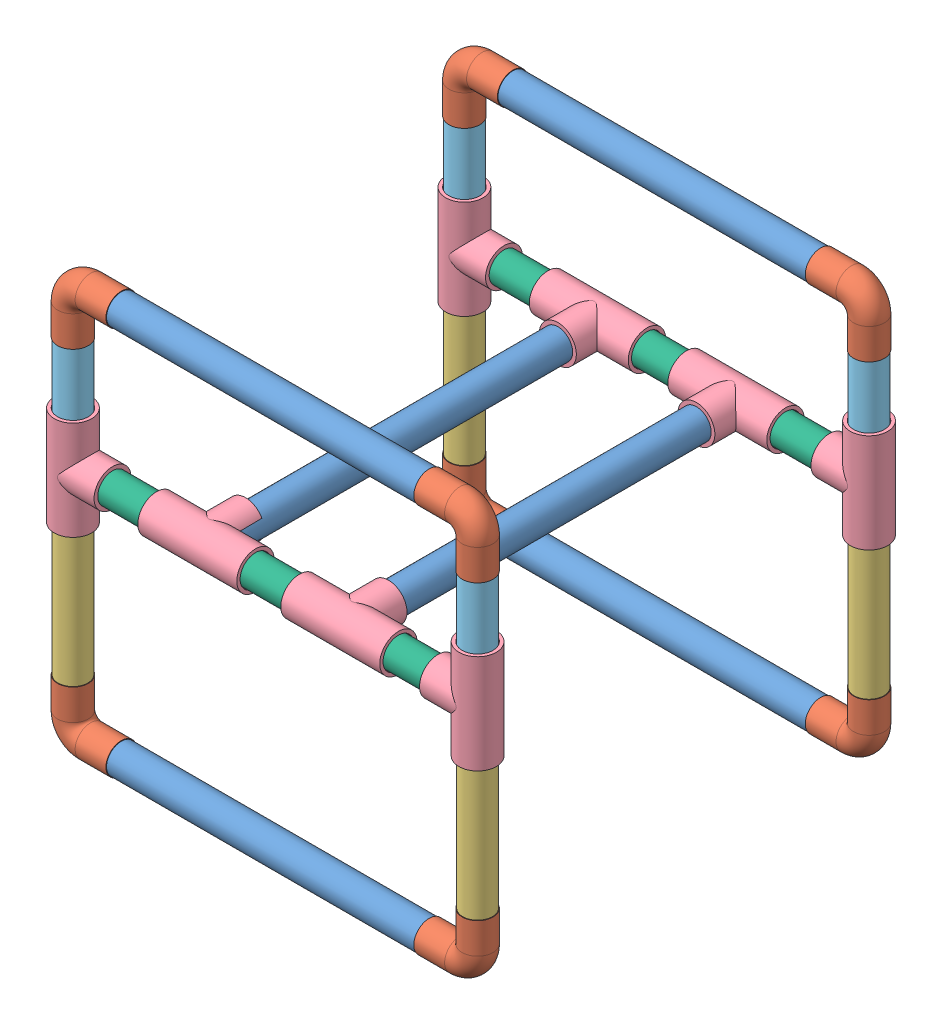
SolidWorks assembly Assem1, configuration Default. Lengths in mm.
Overall size (323.63 436.19 407.61).
38 component instances, 6 part files, 6 mates.
Components (placement in the parent):
- basic_structure_left-1: basic_structure_left [Default] at (119.2636 -212.7478 -168.3466) x (1 0 0) z (0 -1 0) size (320.45 128.03 303.21)
  - PVC_tube_10-1: PVC_tube_10 [Default] at origin size (254 21.34 21.34)
  - PVC_90-1: PVC_90 [Default] at (1.5875 0 -17.1322) x (-1 0 0) z (0 -1 0) size (46.04 46.04 22.23)
  - PVC_90-2: PVC_90 [Default] at (-255.5875 0 -17.1322) x (1 0 0) z (0 1 0) size (46.04 46.04 22.23)
  - PVC_tube_5-1: PVC_tube_5 [Default] at (19.05 0 -146.05) x (0 0 -1) z (-0.258772 -0.965938 0) size (127 21.34 21.34)
  - PVC_tee-1: PVC_tee [Default] at (19.05 0 -165.8938) x (0 0 -1) z (0 1 0) size (71.44 48.76 26.99)
  - PVC_tube_3-1: PVC_tube_3 [Default] at (19.05 0 -261.9375) x (0 0 -1) z (1 0 0) size (76.2 21.34 21.34)
  - PVC_90-3: PVC_90 [Default] at (1.9178 0 -263.525) x (0 0 1) z (0 -1 0) size (46.04 46.04 22.23)
  - PVC_tube_10-2: PVC_tube_10 [Default] at (0 0 -280.9875) size (254 21.34 21.34)
  - PVC_90-4: PVC_90 [Default] at (-255.5875 0 -263.8553) x (1 0 0) z (0 -1 0) size (46.04 46.04 22.23)
  - PVC_tee-2: PVC_tee [Default] at (-273.05 0 -165.8938) x (0 0 -1) z (0 -1 0) size (71.44 48.76 26.99)
  - PVC_tube_3-2: PVC_tube_3 [Default] at (-273.05 0 -185.7375) x (0 0 1) z (0.996828 -0.079586 0) size (76.2 21.34 21.34)
  - PVC_tube_5-2: PVC_tube_5 [Default] at (-273.05 0 -19.05) x (0 0 1) z (-0.574029 0.818835 0) size (127 21.34 21.34)
  - PVC_tube_2.5-1: PVC_tube_2.5 [Default] at (-196.85 0 -165.8938) x (1 0 0) z (0 -0.97364 0.228092) size (63.5 21.34 21.34)
  - PVC_tube_2.5-2: PVC_tube_2.5 [Default] at (-93.6625 0 -165.8938) x (1 0 0) z (0 -0.968379 0.249483) size (63.5 21.34 21.34)
  - PVC_tube_2.5-3: PVC_tube_2.5 [Default] at (6.35 0 -165.8938) size (63.5 21.34 21.34)
  - PVC_tee-6: PVC_tee [Default] at (-177.0062 0 -165.8938) size (71.44 48.76 26.99)
  - PVC_tee-7: PVC_tee [Default] at (-76.9938 0 -165.8938) size (71.44 48.76 26.99)
- basic_structure_right-1: basic_structure_right [Default] at (116.0886 -212.7478 111.0534) x (1 0 0) z (0 -1 0) size (320.45 108.06 303.21)
  - PVC_tube_10-1: PVC_tube_10 [Default] at origin size (254 21.34 21.34)
  - PVC_90-1: PVC_90 [Default] at (1.5875 0 -17.1322) x (-1 0 0) z (0 -1 0) size (46.04 46.04 22.23)
  - PVC_90-2: PVC_90 [Default] at (-255.5875 0 -17.1322) x (1 0 0) z (0 1 0) size (46.04 46.04 22.23)
  - PVC_tube_5-1: PVC_tube_5 [Default] at (19.05 0 -146.05) x (0 0 -1) z (-0.258772 -0.965938 0) size (127 21.34 21.34)
  - PVC_tee-1: PVC_tee [Default] at (19.05 0 -165.8938) x (0 0 -1) z (0 1 0) size (71.44 48.76 26.99)
  - PVC_tube_3-1: PVC_tube_3 [Default] at (19.05 0 -261.9375) x (0 0 -1) z (1 0 0) size (76.2 21.34 21.34)
  - PVC_90-3: PVC_90 [Default] at (1.9178 0 -263.525) x (0 0 1) z (0 -1 0) size (46.04 46.04 22.23)
  - PVC_tube_10-2: PVC_tube_10 [Default] at (0 0 -280.9875) size (254 21.34 21.34)
  - PVC_90-4: PVC_90 [Default] at (-255.5875 0 -263.8553) x (1 0 0) z (0 -1 0) size (46.04 46.04 22.23)
  - PVC_tee-2: PVC_tee [Default] at (-273.05 0 -165.8938) x (0 0 -1) z (0 -1 0) size (71.44 48.76 26.99)
  - PVC_tube_3-2: PVC_tube_3 [Default] at (-273.05 0 -185.7375) x (0 0 1) z (0.996828 -0.079586 0) size (76.2 21.34 21.34)
  - PVC_tube_5-2: PVC_tube_5 [Default] at (-273.05 0 -19.05) x (0 0 1) z (-0.574029 0.818835 0) size (127 21.34 21.34)
  - PVC_tee-3: PVC_tee [Default] at (-177.0062 0 -165.8938) x (1 0 0) z (0 0 -1) size (71.44 48.76 26.99)
  - PVC_tube_2.5-1: PVC_tube_2.5 [Default] at (-196.85 0 -165.8938) x (1 0 0) z (0 -0.97364 0.228092) size (63.5 21.34 21.34)
  - PVC_tube_2.5-2: PVC_tube_2.5 [Default] at (-93.6625 0 -165.8938) x (1 0 0) z (0 -0.968379 0.249483) size (63.5 21.34 21.34)
  - PVC_tee-5: PVC_tee [Default] at (-73.8188 0 -165.8938) x (1 0 0) z (0 0 -1) size (71.44 48.76 26.99)
  - PVC_tube_2.5-3: PVC_tube_2.5 [Default] at (6.35 0 -165.8938) size (63.5 21.34 21.34)
- PVC_tube_10-1: PVC_tube_10 [Default] at (42.2699 -46.854 -155.6466) x (0 0 -1) z (1 0 0) size (254 21.34 21.34)
- PVC_tube_10-2: PVC_tube_10 [Default] at (-57.7426 -46.854 -155.6466) x (0 0 -1) z (1 0 0) size (254 21.34 21.34)
Mates (geometry in assembly coordinates):
- Concentric1: concentric anti-aligned: circle of basic_structure_left-1/PVC_tee-7; circle of PVC_tube_10-1
- Distance1: distance = 15.875 mm anti-aligned: plane of PVC_tube_10-1 through (42.2699 -46.854 -155.6466) normal (0 0 -1); plane of basic_structure_left-1/PVC_tee-7 through (42.2699 -46.854 -139.7716) normal (0 0 1)
- Concentric2: concentric aligned: circle of basic_structure_right-1/PVC_tee-5; circle of PVC_tube_10-1
- Distance2: distance = 15.875 mm anti-aligned: plane of PVC_tube_10-1 through (42.2699 -46.854 98.3534) normal (0 0 1); plane of basic_structure_right-1/PVC_tee-5 through (42.2699 -46.854 82.4784) normal (0 0 -1)
- Concentric3: concentric anti-aligned: circle of basic_structure_left-1/PVC_tee-6; circle of PVC_tube_10-2
- Distance3: distance = 15.875 mm anti-aligned: plane of PVC_tube_10-2 through (-57.7426 -46.854 -155.6466) normal (0 0 -1); plane of basic_structure_left-1/PVC_tee-6 through (-57.7426 -46.854 -139.7716) normal (0 0 1)
